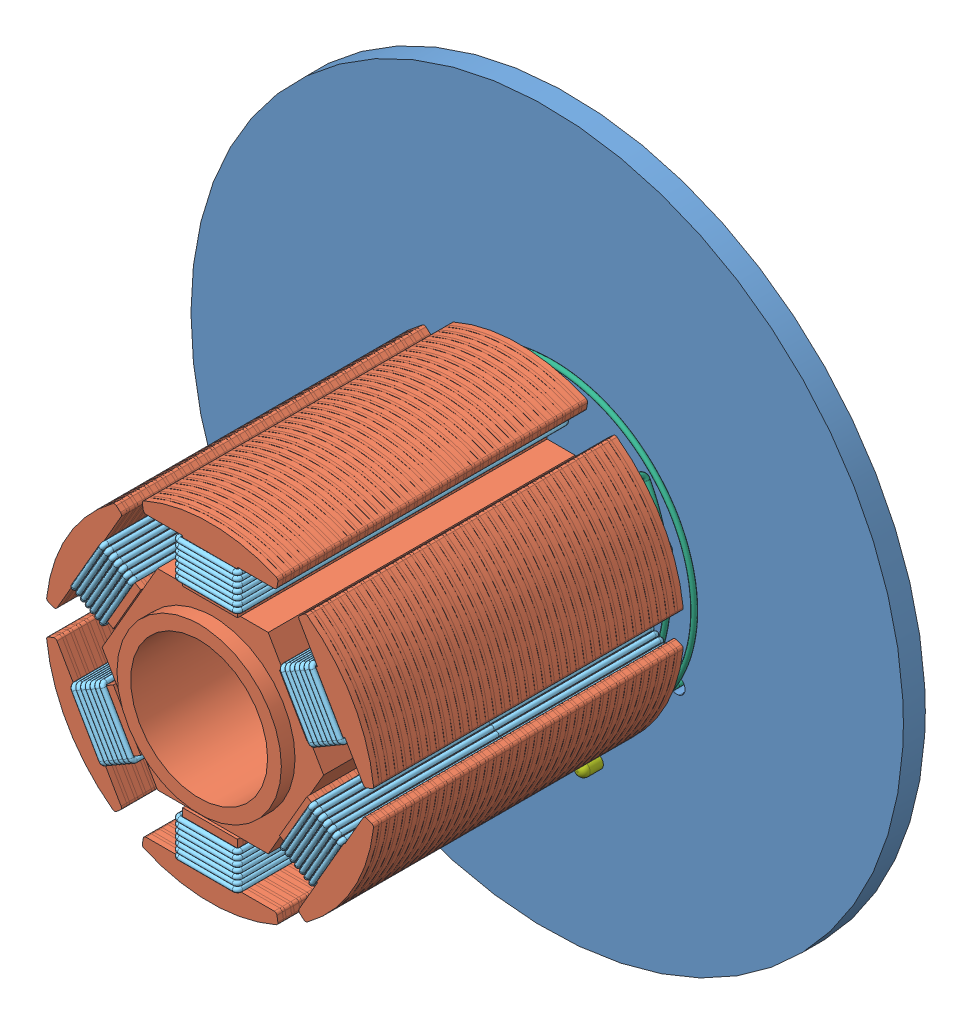
SolidWorks assembly Brushless motor A6x25, configuration Predeterminado. Lengths in mm.
Overall size (26 26 15.1).
12 component instances, 7 part files, 20 mates.
Components (placement in the parent):
- Board A6x25-1: Board A6x25 [Predeterminado] at origin size (26 26 0.8)
- Stator A6x25-1: Stator A6x25 [Predeterminado] at (0 0 0.8) size (11.93 12 11.7)
- Hall Effect sensor A6x25-1: Hall Effect sensor A6x25 [WE] at (-5.3023 -0.9391 0) x (-0.233503 0.972356 0) z (-0.972356 -0.233503 0) size (6.3 1.6 2.6)
- Controller A6x25-1: Controller A6x25 [Predeterminado] at (5.1574 2.3195 0) x (0.319288 -0.947658 0) z (0.947658 0.319288 0) size (4.81 0.99 3)
- Coil A6x25-1: Coil A6x25 [Predeterminado] at (0 -5.01 1.29) x (-1 0 0) z (0 1 0) size (2.38 12.19 1.58)
- Coil A6x25-2: Coil A6x25 [Predeterminado] at (4.3388 -2.505 1.29) x (-0.5 -0.866025 0) z (-0.866025 0.5 0) size (2.38 12.19 1.58)
- Coil A6x25-3: Coil A6x25 [Predeterminado] at (4.3388 2.505 1.29) x (0.5 -0.866025 0) z (-0.866025 -0.5 0) size (2.38 12.19 1.58)
- Coil A6x25-4: Coil A6x25 [Predeterminado] at (0 5.01 1.29) x (1 0 0) z (0 -1 0) size (2.38 12.19 1.58)
- Coil A6x25-5: Coil A6x25 [Predeterminado] at (-4.3388 2.505 1.29) x (0.5 0.866025 0) z (0.866025 -0.5 0) size (2.38 12.19 1.58)
- Coil A6x25-6: Coil A6x25 [Predeterminado] at (-4.3388 -2.505 1.29) x (-0.5 0.866025 0) z (0.866025 0.5 0) size (2.38 12.19 1.58)
- Pieza2^Brushless motor A6x25-1: Pieza2^Brushless motor A6x25 [Predeterminado] at origin size (10.72 12.51 6.88) (virtual)
- Pieza3^Brushless motor A6x25-1: Pieza3^Brushless motor A6x25 [Predeterminado] at (0 0 0.8) size (4.1 0.74 1.7) (virtual)
Mates (geometry in assembly coordinates):
- Coincidente1: coincident aligned: plane of Board A6x25-1 through (0 0 0) normal (0 0 1)
- Coincidente2: coincident aligned: plane of Board A6x25-1 through (0 0 0) normal (0 1 0)
- Coincidente3: coincident aligned: plane of Board A6x25-1 through (0 0 0) normal (1 0 0)
- Bloquear1: lock: unknown of Board A6x25-1; unknown of Hall Effect sensor-1
- Coincidente16: coincident anti-aligned: plane of Board A6x25-1 through (0 0 0) normal (0 0 -1); plane of Controller-1 through (5.1574 2.3195 0) normal (0 0 1)
- Bloquear2: lock: unknown of Board A6x25-1; unknown of Controller-1
- Coincidente17: coincident anti-aligned: plane of Coil A6x25-1 through (0 -5.01 1.29) normal (-1 0 0)
- Paralelo1: parallel aligned: plane of Coil A6x25-1 through (0 -5.01 1.29) normal (0 0 1)
- Bloquear3: lock: unknown of Board A6x25-1; unknown of Coil A6x25-1
- EnPosición1: in place: plane of ? through (0 0 0) normal (0 0 1); moOrthogonalPlaneRef_w of ? through (0 0 0) normal (0 1 0); plane of ? through (0 0 0) normal (1 0 0); unknown of ?
- Coincidente18: coincident aligned: 
- Coincidente19: coincident aligned: plane of Pieza2^Brushless motor-1 through (0 0 0) normal (0 1 0)
- Coincidente20: coincident anti-aligned: plane of Pieza2^Brushless motor-1 through (0 0 0) normal (1 0 0)
- EnPosición2: in place: plane of ? through (0 0 0.8) normal (0 0 1); plane of ? through (0 0 0.8) normal (0 0 1); plane of ? through (0 0 0.8) normal (0 0 1); plane of ? through (0 0 0.8) normal (0 1 0); plane of ? through (0 0 0.8) normal (0 0 1); plane of ? through (0 0 0.8) normal (1 0 0); plane of ? through (0 0 0.8) normal (0 0 1); unknown of ?
- Coincidente21: coincident aligned: plane of ?; plane of ?
- Coincidente22: coincident aligned: moOrthogonalPlaneRef_w of Board A6x25-1 through (0 0 0.8) normal (0 1 0); plane of Pieza3^Brushless motor-1 through (0 0 0.8) normal (0 1 0)
- Coincidente23: coincident anti-aligned: moOrthogonalPlaneRef_w of Board A6x25-1 through (0 0 0.8) normal (-1 0 0); plane of Pieza3^Brushless motor-1 through (0 0 0.8) normal (1 0 0)
- Coincident1: coincident aligned: plane of Board A6x25-1 through (0 0 0.8) normal (0 0 1); plane of Stator A6x25-1 through (0 0 0.8) normal (0 0 1)
- Concentric1: concentric anti-aligned: cylinder of Board A6x25-1 through (0 0 0.8) axis (0 0 -1) radius 13; cylinder of Stator A6x25-1 through (0 0 -7.6853) axis (0 0 1) radius 2.5
- Coincident2: coincident aligned: plane of Stator A6x25-1 through (0 0 0.8) normal (0 1 0)
